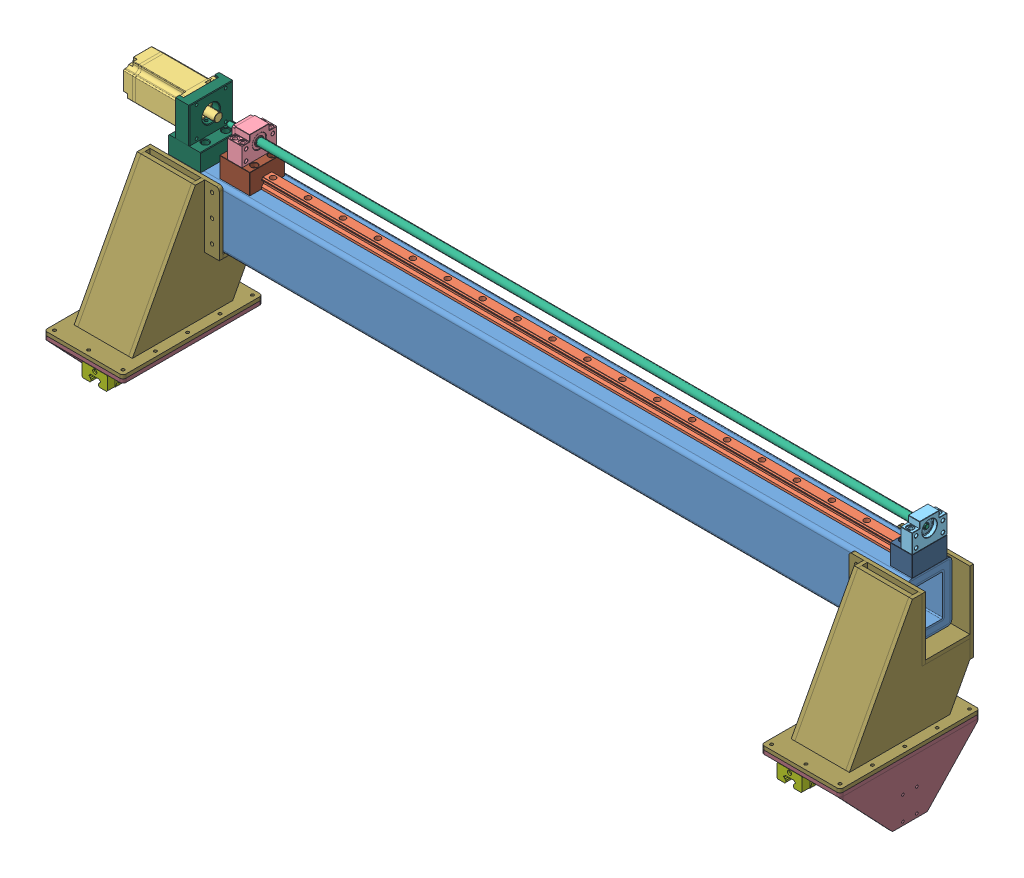
SolidWorks assembly Gantry, configuration Default. Lengths in mm.
Overall size (1404.15 401.35 247).
30 component instances, 15 part files, 148 mates.
Components (placement in the parent):
- steel gantry-1: steel gantry [CFDST] x (0 0 -1) z (1 0 0) size (76.2 101.6 1270)
- HGR20-1: HGR20 [gantry] at (0 -65.3657 0) x (0 0 -1) z (-1 0 0) size (20 17.5 1100)
- HGR20-2: HGR20 [gantry] at (47 65.2343 0) x (0 0 -1) z (1 0 0) size (20 17.5 1100)
- servo JMC_400W_AC-1: servo JMC_400W_AC [Default] at (-704.5 110.7343 0) x (0 -1 0) z (0 0 1) size (60 133.6 60)
- BK12-1: BK12 [Default] at (-529 110.7343 0) x (0 0 1) z (-1 0 0) size (60 43 30.41)
- BF12-1: BF12 [Default] at (625 110.7343 0) x (0 0 1) z (-1 0 0) size (60 43 20)
- ballscrew-1: ballscrew [X Axis] at (31 110.7343 0) x (0 0 1) z (-1 0 0) size (12.64 12.64 1200)
- HGW20CC-1: HGW20CC [Default] at (-596.9 -181.5657 163.9242) x (0 0 -1) z (1 0 0) size (77.26 24.9 63)
- HGW20CC-2: HGW20CC [Default] at (-596.9 -181.5657 1.1842) x (0 0 -1) z (1 0 0) size (77.26 24.9 63)
- HGW20CC-3: HGW20CC [Default] at (596.9 -181.5657 163.9242) x (0 0 1) z (-1 0 0) size (77.26 24.9 63)
- HGW20CC-4: HGW20CC [Default] at (596.9 -181.5657 1.1842) x (0 0 1) z (-1 0 0) size (77.26 24.9 63)
- SFU1610 nut housing-1: SFU1610 nut housing [Default] at (-657.3 -234.3657 62.5542) x (0 -1 0) z (0 0 1) size (52 40 40)
- nut_XY-1: nut_XY [Default] at (-657.3 -234.3657 90.5542) x (0 -1 0) z (0 0 1) size (48 40 44)
- nut_XY-2: nut_XY [Default] at (657.3 -234.3657 90.5542) x (0 1 0) z (0 0 1) size (48 40 44)
- SFU1610 nut housing-2: SFU1610 nut housing [Default] at (657.3 -234.3657 62.5542) x (0 1 0) z (0 0 1) size (52 40 40)
- BF12 lift-1: BF12 lift [Default] at (616 50.7343 0) x (0 0 -1) z (1 0 0) size (60 35 38)
- BK12 front block-1: BK12 front block [Default] at (-529 50.7343 0) x (0 0 -1) z (1 0 0) size (60 35 52)
- Gantry Riser Top-1: Gantry Riser Top [Left<As Machined>] at (-616.075 -152.8657 82.5542) size (142.58 209.95 247)
- Gantry Riser Bottom-1: Gantry Riser Bottom [Left] at (-616.075 -159.2157 82.5542) size (135.15 101.15 240)
- Gantry Riser Bottom-2: Gantry Riser Bottom [Right] at (616.075 -159.2157 82.5542) size (135.15 101.15 240)
- Gantry Riser Top-2: Gantry Riser Top [Right] at (616.075 -152.8657 82.5542) size (142.58 209.95 247)
- socket head cap screw_am-1: socket head cap screw_am [B18.3.1M - 6 x 1.0 x 16 Hex SHCS -- 16NHX] at (-570.4 -153.2157 183.9242) x (0 -1 0) z (0 0 1) size (22 10 10)
- socket head cap screw_am-2: socket head cap screw_am [B18.3.1M - 6 x 1.0 x 16 Hex SHCS -- 16NHX] at (-570.4 -153.2157 143.9242) x (0 -1 0) z (0 0 1) size (22 10 10)
- socket head cap screw_am-3: socket head cap screw_am [B18.3.1M - 6 x 1.0 x 16 Hex SHCS -- 16NHX] at (-623.4 -153.2157 143.9242) x (0 -1 0) z (0 0 1) size (22 10 10)
- socket head cap screw_am-4: socket head cap screw_am [B18.3.1M - 6 x 1.0 x 16 Hex SHCS -- 16NHX] at (-623.4 -153.2157 183.9242) x (0 -1 0) z (0 0 1) size (22 10 10)
- socket head cap screw_am-6: socket head cap screw_am [B18.3.1M - 6 x 1.0 x 16 Hex SHCS -- 16NHX] at (-570.4 -153.2157 -18.8158) x (0 -1 0) z (0 0 1) size (22 10 10)
- socket head cap screw_am-7: socket head cap screw_am [B18.3.1M - 6 x 1.0 x 16 Hex SHCS -- 16NHX] at (-623.4 -153.2157 -18.8158) x (0 -1 0) z (0 0 1) size (22 10 10)
- socket head cap screw_am-8: socket head cap screw_am [B18.3.1M - 6 x 1.0 x 16 Hex SHCS -- 16NHX] at (-570.4 -153.2157 21.1842) x (0 -1 0) z (0 0 1) size (22 10 10)
- socket head cap screw_am-9: socket head cap screw_am [B18.3.1M - 6 x 1.0 x 16 Hex SHCS -- 16NHX] at (-623.4 -153.2157 21.1842) x (0 -1 0) z (0 0 1) size (22 10 10)
- X Servo Mount-1: X Servo Mount [Default] at (-611.5 110.7343 0) x (0 0 1) z (-1 0 0) size (75 90.25 55)
Mates (geometry in assembly coordinates):
- Coincident2: coincident: point of steel gantry-1
- Coincident3: coincident aligned: plane of steel gantry-1 through (0 0 0) normal (0 1 0)
- Coincident5: coincident anti-aligned: plane of steel gantry-1 through (0 0 0) normal (0 0 -1)
- Coincident7: coincident anti-aligned: plane of steel gantry-1 through (635 50.7343 31.75) normal (0 1 0); plane of BK12 back block gantry-1 through (635 50.7343 37.9) normal (0 -1 0)
- Coincident10: coincident anti-aligned: plane of steel gantry-1 through (635 50.7343 31.75) normal (0 1 0); plane of HGR20-2 through (597 50.7343 10) normal (0 -1 0)
- Width1: width anti-aligned: plane of steel gantry-1 through (635 -44.5157 38.1) normal (0 0 1); plane of steel gantry-1 through (635 44.3843 -38.1) normal (0 0 -1); plane of HGR20-2 through (597 54.5843 -10) normal (0 0 -1); plane of HGR20-2 through (597 54.5843 10) normal (0 0 1)
- Coincident11: coincident anti-aligned: plane of HGR20-2 through (-503 62.5879 9.6464) normal (-1 0 0); plane of BK12 front block gantry-1 through (-503 75.1343 0.1) normal (1 0 0)
- Coincident12: coincident anti-aligned: plane of steel gantry-1 through (635 50.7343 31.75) normal (0 1 0); plane of BK12 front block gantry-1 through (-556.5 50.7343 -37.9) normal (0 -1 0)
- Coincident13: coincident anti-aligned: plane of steel gantry-1 through (635 -44.5157 38.1) normal (0 0 1); plane of BK12 front block gantry-1 through (-556.5 25.3343 38.1) normal (0 0 -1)
- Coincident14: coincident anti-aligned: plane of steel gantry-1 through (635 50.7343 31.75) normal (0 1 0); plane of servo mount gantry-1 through (-580 50.7343 38.1) normal (0 -1 0)
- Coincident15: coincident anti-aligned: plane of steel gantry-1 through (635 -44.5157 38.1) normal (0 0 1); plane of servo mount gantry-1 through (-580 50.7343 38.1) normal (0 0 -1)
- Coincident16: coincident aligned: plane of steel gantry-1 through (-635 -44.5157 31.75) normal (-1 0 0); plane of servo mount gantry-1 through (-635 106.1843 -0.525) normal (-1 0 0)
- Parallel1: parallel: plane of servo mount gantry-1 through (-635 136.4343 46.975) normal (0 1 0); plane of servo JMC_400W_AC-1 through (-616.5 140.7343 -30) normal (0 1 0)
- Concentric2: concentric aligned: cylinder of BK12 front block gantry-1 through (-536.25 59.1343 23.1) axis (0 1 0) radius 2.9; cylinder of BK12-1 through (-535.5 85.7343 23) axis (0 1 0) radius 3.3
- Parallel2: parallel aligned: plane of BK12 front block gantry-1 through (-556.5 75.1343 0.1) normal (-1 0 0); plane of BK12-1 through (-541.5 110.7343 0) normal (-1 0 0)
- Coincident20: coincident anti-aligned: plane of BK12 front block gantry-1 through (-556.5 81.1343 48.2) normal (0 1 0); plane of BK12-1 through (-541.5 85.7343 -30) normal (0 -1 0)
- Parallel3: parallel aligned: plane of steel gantry-1 through (635 -44.5157 38.1) normal (0 0 1); plane of BF12-1 through (615 118.2343 30) normal (0 0 1)
- Coincident22: coincident anti-aligned: plane of BK12 back block gantry-1 through (635 81.1343 -48.2) normal (0 1 0); plane of BF12-1 through (615 85.7343 -30) normal (0 -1 0)
- Coincident23: coincident anti-aligned: plane of BF12-1 through (621 110.7343 -8.1511) normal (-1 0 0); plane of ballscrew-1 through (621 117.0543 0) normal (1 0 0)
- Concentric5: concentric aligned: cylinder of BF12-1 through (625 110.7343 0) axis (-1 0 0) radius 5; cylinder of ballscrew-1 through (-569 110.7343 0) axis (-1 0 0) radius 6.32
- Coincident24: coincident aligned: plane of steel gantry-1 through (635 -44.5157 31.75) normal (1 0 0); plane of BK12 back block gantry-1 through (635 75.1343 -0.1) normal (1 0 0)
- Coincident25: coincident anti-aligned: plane of steel gantry-1 through (635 44.3843 -38.1) normal (0 0 -1); plane of BK12 back block gantry-1 through (635 25.3343 -38.1) normal (0 0 1)
- Coincident26: coincident anti-aligned: plane of HGR20-2 through (597 62.5879 9.6464) normal (1 0 0); plane of BK12 back block gantry-1 through (597 75.1343 -0.1) normal (-1 0 0)
- Concentric6: concentric aligned: cylinder of BK12 back block gantry-1 through (623 58.1343 -23.1) axis (0 1 0) radius 2.9; cylinder of BF12-1 through (625 85.7343 -23) axis (0 1 0) radius 3.3
- Coincident27: coincident anti-aligned: plane of steel gantry-1 through (635 -50.8657 -31.75) normal (0 -1 0); plane of HGR20-1 through (-550 -50.8657 10) normal (0 1 0)
- Width2: width anti-aligned: plane of steel gantry-1 through (635 44.3843 -38.1) normal (0 0 -1); plane of steel gantry-1 through (635 -44.5157 38.1) normal (0 0 1); plane of HGR20-1 through (-550 -54.7157 10) normal (0 0 1); plane of HGR20-1 through (-550 -54.7157 -10) normal (0 0 -1)
- Width3: width anti-aligned: plane of steel gantry-1 through (635 -44.5157 31.75) normal (1 0 0); plane of steel gantry-1 through (-635 -44.5157 31.75) normal (-1 0 0); plane of HGR20-1 through (-550 -62.7192 9.6464) normal (-1 0 0); plane of HGR20-1 through (550 -62.7192 9.6464) normal (1 0 0)
- Parallel4: parallel aligned: plane of ballscrew-1 through (31 110.7343 0) normal (0 1 0)
- Coincident30: coincident aligned: plane of steel gantry-1 through (635 50.7343 31.75) normal (0 1 0); plane of gantry risers-1 through (-647.7 50.7343 176.5) normal (0 1 0)
- Coincident31: coincident anti-aligned: plane of gantry risers-1 through (-356.4052 -165.3757 176.5) normal (0 -1 0); plane of HGW20CC-2 through (-591.545 -165.5657 -77.5988) normal (0 1 0)
- Width5: width anti-aligned: plane of gantry risers-1 through (-647.7 -165.3757 176.5) normal (-1 0 0); plane of gantry risers-1 through (-542.3 -165.3757 176.5) normal (1 0 0); plane of HGW20CC-2 through (-565.4 -174.9214 -77.5988) normal (1 0 0); plane of HGW20CC-2 through (-628.4 -174.9214 -77.5988) normal (-1 0 0)
- Coincident33: coincident aligned: plane of gantry risers-1 through (-356.4052 -165.3757 -21.6883) normal (0 0 -1); plane of HGW20CC-2 through (-587.2536 -178.9042 -37.4458) normal (0 0 -1)
- Coincident35: coincident anti-aligned: plane of steel gantry-1 through (-635 -44.5157 31.75) normal (-1 0 0); plane of gantry risers-1 through (-635 -165.3757 176.5) normal (1 0 0)
- Coincident37: coincident anti-aligned: plane of steel gantry-1 through (635 -44.5157 38.1) normal (0 0 1); plane of gantry risers-1 through (-351.1939 -165.3757 38.1) normal (0 0 -1)
- Coincident38: coincident anti-aligned: plane of steel gantry-1 through (635 -44.5157 31.75) normal (1 0 0); plane of gantry risers-2 through (635 -165.2707 176.5) normal (-1 0 0)
- Coincident39: coincident anti-aligned: plane of steel gantry-1 through (635 -44.5157 38.1) normal (0 0 1); plane of gantry risers-2 through (838.8061 -165.2707 38.1) normal (0 0 -1)
- Coincident40: coincident anti-aligned: plane of steel gantry-1 through (635 -50.8657 -31.75) normal (0 -1 0); plane of gantry risers-2 through (371.3 -50.8657 -33.1) normal (0 1 0)
- Coincident41: coincident anti-aligned: plane of gantry risers-2 through (833.5948 -165.2707 176.5) normal (0 -1 0); plane of HGW20CC-4 through (565.4 -165.5657 79.9672) normal (0 1 0)
- Coincident42: coincident anti-aligned: plane of gantry risers-2 through (833.5948 -165.2707 176.5) normal (0 -1 0); plane of HGW20CC-3 through (591.545 -165.5657 242.7072) normal (0 1 0)
- Coincident43: coincident aligned: plane of gantry risers-2 through (833.5948 -165.2707 176.5) normal (0 0 1); plane of HGW20CC-3 through (587.2536 -178.9042 202.5542) normal (0 0 1)
- Coincident44: coincident aligned: plane of gantry risers-2 through (833.5948 -165.2707 -21.6883) normal (0 0 -1); plane of HGW20CC-4 through (587.2536 -178.9042 -37.4458) normal (0 0 -1)
- Coincident45: coincident aligned: plane of HGW20CC-3 through (628.4 -174.9214 242.7072) normal (1 0 0); plane of HGW20CC-4 through (628.4 -174.9214 79.9672) normal (1 0 0)
- Width6: width aligned: plane of HGW20CC-3 through (628.4 -174.9214 242.7072) normal (1 0 0); plane of HGW20CC-3 through (565.4 -174.9214 242.7072) normal (-1 0 0); plane of gantry risers-2 through (647.7 -165.2707 176.5) normal (1 0 0); plane of gantry risers-2 through (542.3 -165.2707 176.5) normal (-1 0 0)
- Coincident46: coincident anti-aligned: plane of steel gantry-1 through (635 -44.5157 38.1) normal (0 0 1); plane of steel risers-1 through (-635 50.8393 38.1) normal (0 0 -1)
- Coincident47: coincident anti-aligned: plane of steel gantry-1 through (635 -50.8657 -31.75) normal (0 -1 0); plane of steel risers-1 through (-635 -50.8657 33.1) normal (0 1 0)
- Coincident48: coincident aligned: plane of steel gantry-1 through (-635 -44.5157 31.75) normal (-1 0 0); plane of steel risers-1 through (-635 138.1706 -0.2312) normal (-1 0 0)
- Coincident49: coincident aligned: plane of steel gantry-1 through (-635 -44.5157 31.75) normal (-1 0 0); plane of steel plate gantry risers-1 through (-635 -165.1526 176.2522) normal (-1 0 0)
- Coincident50: coincident anti-aligned: plane of steel gantry-1 through (635 -44.5157 38.1) normal (0 0 1); plane of steel plate gantry risers-1 through (-548.5 -50.8657 38.1) normal (0 0 -1)
- Coincident51: coincident anti-aligned: plane of steel gantry-1 through (635 -50.8657 -31.75) normal (0 -1 0); plane of steel plate gantry risers-1 through (-548.5 -50.8657 38.1) normal (0 1 0)
- Width7: width aligned: plane of SFU1610 nut housing-1 through (-657.3 -234.3657 102.5542) normal (0 0 1); plane of steel plate gantry risers-1 through (-657.3 -234.3657 62.5542) normal (0 0 -1); plane of SFU1610 nut housing-1 through (-548.5 -158.8157 196) normal (0 0 1); plane of steel plate gantry risers-1 through (-548.5 -158.8157 -44) normal (0 0 -1)
- Concentric7: concentric anti-aligned: cylinder of SFU1610 nut housing-1 through (-657.3 -234.3657 102.5542) axis (0 0 -1) radius 14; cylinder of nut_XY-1 through (-657.3 -234.3657 108.4825) axis (0 0 1) radius 14
- Coincident53: coincident anti-aligned: plane of SFU1610 nut housing-1 through (-657.3 -234.3657 102.5542) normal (0 0 1); plane of nut_XY-1 through (-633.3 -234.3657 102.5542) normal (0 0 -1)
- Coincident54: coincident aligned: plane of SFU1610 nut housing-1 through (-637.3 -220.3657 102.5542) normal (1 0 0); plane of nut_XY-1 through (-637.3 -254.3657 68.5542) normal (1 0 0)
- Coincident65: coincident aligned: plane of steel gantry-1 through (635 -44.5157 31.75) normal (1 0 0); plane of steel plate gantry risers-2 through (635 -165.1526 176.2522) normal (1 0 0)
- Coincident66: coincident anti-aligned: plane of steel gantry-1 through (635 -50.8657 -31.75) normal (0 -1 0); plane of steel plate gantry risers-2 through (548.5 -50.8657 38.1) normal (0 1 0)
- Coincident67: coincident anti-aligned: plane of steel gantry-1 through (635 44.3843 -38.1) normal (0 0 -1); plane of steel plate gantry risers-2 through (548.5 -50.8657 -38.1) normal (0 0 1)
- Coincident68: coincident anti-aligned: plane of HGW20CC-3 through (591.545 -165.5657 242.7072) normal (0 1 0); plane of steel plate gantry risers-2 through (595 -165.1657 176.2522) normal (0 -1 0)
- Coincident69: coincident anti-aligned: plane of HGW20CC-4 through (591.545 -165.5657 79.9672) normal (0 1 0); plane of steel plate gantry risers-2 through (595 -165.1657 176.2522) normal (0 -1 0)
- Coincident70: coincident aligned: plane of HGW20CC-3 through (587.2536 -178.9042 202.5542) normal (0 0 1); plane of steel plate gantry risers-2 through (548.5 -158.8157 196) normal (0 0 1)
- Coincident71: coincident aligned: plane of HGW20CC-4 through (587.2536 -178.9042 -37.4458) normal (0 0 -1); plane of steel plate gantry risers-2 through (548.5 -158.8157 -44) normal (0 0 -1)
- Coincident73: coincident aligned: plane of SFU1610 nut housing-1 through (-657.3 -234.3657 102.5542) normal (0 0 1); plane of SFU1610 nut housing-2 through (657.3 -234.3657 102.5542) normal (0 0 1)
- Concentric8: concentric anti-aligned: cylinder of nut_XY-2 through (657.3 -234.3657 108.4825) axis (0 0 1) radius 14; cylinder of SFU1610 nut housing-2 through (657.3 -234.3657 102.5542) axis (0 0 -1) radius 14
- Coincident75: coincident aligned: plane of nut_XY-2 through (637.3 -214.3657 68.5542) normal (-1 0 0); plane of SFU1610 nut housing-2 through (637.3 -248.3657 102.5542) normal (-1 0 0)
- Coincident76: coincident anti-aligned: plane of nut_XY-2 through (633.3 -234.3657 102.5542) normal (0 0 -1); plane of SFU1610 nut housing-2 through (657.3 -234.3657 102.5542) normal (0 0 1)
- Concentric9: concentric aligned: cylinder of BF12-1 through (625 85.7343 -23) axis (0 1 0) radius 3.3; cylinder of BF12 lift-1 through (625 50.7343 -23) axis (0 1 0) radius 2.9
- Concentric10: concentric aligned: cylinder of BF12-1 through (625 85.7343 23) axis (0 1 0) radius 3.3; cylinder of BF12 lift-1 through (625 50.7343 23) axis (0 1 0) radius 2.9
- Coincident77: coincident anti-aligned: plane of BF12-1 through (615 85.7343 -30) normal (0 -1 0); plane of BF12 lift-1 through (616 85.7343 0) normal (0 1 0)
- Coincident78: coincident aligned: plane of steel gantry-1 through (635 -44.5157 31.75) normal (1 0 0); plane of BF12 lift-1 through (635 85.7343 -30) normal (1 0 0)
- Coincident79: coincident anti-aligned: plane of steel gantry-1 through (635 50.7343 31.75) normal (0 1 0); plane of BF12 lift-1 through (616 50.7343 0) normal (0 -1 0)
- Width8: width anti-aligned: plane of BF12 lift-1 through (597 85.7343 30) normal (0 0 1); plane of BF12 lift-1 through (597 85.7343 -30) normal (0 0 -1); plane of steel gantry-1 through (635 44.3843 -38.1) normal (0 0 -1); plane of steel gantry-1 through (635 -44.5157 38.1) normal (0 0 1)
- Concentric11: concentric anti-aligned: cylinder of BK12-1 through (-522.5 85.7343 23) axis (0 1 0) radius 3.3; cylinder of BK12 front block-1 through (-522.5 85.7343 23) axis (0 -1 0) radius 2.9
- Concentric12: concentric anti-aligned: cylinder of BK12-1 through (-522.5 85.7343 -23) axis (0 1 0) radius 3.3; cylinder of BK12 front block-1 through (-522.5 85.7343 -23) axis (0 -1 0) radius 2.9
- Coincident80: coincident anti-aligned: plane of BK12-1 through (-541.5 85.7343 -30) normal (0 -1 0); plane of BK12 front block-1 through (-529 85.7343 0) normal (0 1 0)
- Coincident81: coincident anti-aligned: plane of steel gantry-1 through (635 50.7343 31.75) normal (0 1 0); plane of BK12 front block-1 through (-529 50.7343 0) normal (0 -1 0)
- Width9: width aligned: plane of BK12 front block-1 through (-503 85.7343 30) normal (0 0 1); plane of BK12 front block-1 through (-503 85.7343 -30) normal (0 0 -1); plane of steel gantry-1 through (635 -44.5157 38.1) normal (0 0 1); plane of steel gantry-1 through (635 44.3843 -38.1) normal (0 0 -1)
- Coincident82: coincident anti-aligned: plane of HGR20-2 through (-503 62.5879 9.6464) normal (-1 0 0); plane of BK12 front block-1 through (-503 85.7343 -30) normal (1 0 0)
- Coincident83: coincident anti-aligned: plane of HGR20-2 through (597 62.5879 9.6464) normal (1 0 0); plane of BF12 lift-1 through (597 85.7343 -30) normal (-1 0 0)
- Concentric14: concentric aligned: cylinder of servo JMC_400W_AC-1 through (-540.501 110.7343 0) axis (-1 0 0) radius 7; cylinder of ballscrew-1 through (-569 110.7343 0) axis (-1 0 0) radius 4
- Coincident84: coincident anti-aligned: plane of steel gantry-1 through (635 50.7343 31.75) normal (0 1 0); plane of servo motor mount-1 through (-610.5 50.7343 0) normal (0 -1 0)
- Concentric15: concentric anti-aligned: cylinder of servo JMC_400W_AC-1 through (-540.501 110.7343 0) axis (-1 0 0) radius 7; cylinder of servo motor mount-1 through (-616.5 110.7343 0) axis (1 0 0) radius 15
- Coincident85: coincident anti-aligned: plane of servo JMC_400W_AC-1 through (-613.5 110.7343 0) normal (1 0 0); plane of servo motor mount-1 through (-613.5 110.7343 0) normal (-1 0 0)
- Coincident86: coincident aligned: plane of steel gantry-1 through (-635 -44.5157 31.75) normal (-1 0 0); plane of servo motor mount-1 through (-635 50.7343 -42.25) normal (-1 0 0)
- Coincident89: coincident aligned: plane of HGW20CC-2 through (-587.2536 -178.9042 -37.4458) normal (0 0 -1); plane of steel plate gantry risers-1 through (-548.5 -158.8157 -44) normal (0 0 -1)
- Coincident90: coincident aligned: plane of HGW20CC-1 through (-587.2536 -178.9042 202.5542) normal (0 0 1); plane of steel plate gantry risers-1 through (-548.5 -158.8157 196) normal (0 0 1)
- Coincident91: coincident anti-aligned: plane of HGW20CC-1 through (-591.545 -165.5657 85.1412) normal (0 1 0); plane of steel plate gantry risers-1 through (-595 -165.1657 176.2522) normal (0 -1 0)
- Coincident92: coincident anti-aligned: plane of HGW20CC-2 through (-591.545 -165.5657 -77.5988) normal (0 1 0); plane of steel plate gantry risers-1 through (-595 -165.1657 176.2522) normal (0 -1 0)
- Coincident93: coincident aligned: plane of HGW20CC-1 through (-565.4 -174.9214 85.1412) normal (1 0 0); plane of HGW20CC-2 through (-565.4 -174.9214 -77.5988) normal (1 0 0)
- Distance3: distance = 41.9 mm anti-aligned: plane of steel plate gantry risers-1 through (-548.5 -158.8157 -44) normal (1 0 0); plane of HGW20CC-1 through (-590.4 -185.7307 125.2942) normal (-1 0 0)
- Distance4: distance = 41.9 mm anti-aligned: plane of steel plate gantry risers-2 through (548.5 -158.8157 -44) normal (-1 0 0); plane of HGW20CC-3 through (590.4 -185.7307 202.5542) normal (1 0 0)
- Coincident94: coincident anti-aligned: plane of steel plate gantry risers-1 through (-677.3 -165.1657 -151.0833) normal (1 0 0); plane of SFU1610 nut housing-1 through (-677.3 -208.3657 102.5542) normal (-1 0 0)
- Coincident95: coincident aligned: plane of steel plate gantry risers-1 through (-677.3 -259.9657 -151.0833) normal (0 -1 0); plane of SFU1610 nut housing-1 through (-677.3 -260.3657 102.5542) normal (0 -1 0)
- Coincident96: coincident anti-aligned: plane of steel plate gantry risers-2 through (677.3 -165.1657 -151.0833) normal (-1 0 0); plane of SFU1610 nut housing-2 through (677.3 -260.3657 102.5542) normal (1 0 0)
- Coincident97: coincident aligned: plane of steel plate gantry risers-2 through (677.3 -259.9657 -151.0833) normal (0 -1 0); plane of SFU1610 nut housing-2 through (677.3 -260.3657 102.5542) normal (0 -1 0)
- Coincident100: coincident aligned: plane of steel plate gantry risers-1 through (-548.5 -158.8157 196) normal (0 0 1); plane of Gantry Riser Bottom-1 through (-616.075 -159.2157 202.5542) normal (0 0 1)
- Coincident101: coincident aligned: plane of steel plate gantry risers-1 through (-595 -165.1657 176.2522) normal (0 -1 0); plane of Gantry Riser Bottom-1 through (-553.5 -165.5657 202.5642) normal (0 -1 0)
- Coincident102: coincident aligned: plane of steel plate gantry risers-1 through (-548.5 -158.8157 -44) normal (1 0 0); plane of Gantry Riser Bottom-1 through (-548.5 -165.5657 202.5542) normal (1 0 0)
- Coincident103: coincident aligned: plane of Gantry Riser Top-1 through (-548.5 -159.2157 202.5542) normal (0 0 1); plane of Gantry Riser Bottom-1 through (-616.075 -159.2157 202.5542) normal (0 0 1)
- Coincident104: coincident aligned: plane of Gantry Riser Top-1 through (-548.5 -159.2157 -37.4458) normal (1 0 0); plane of Gantry Riser Bottom-1 through (-548.5 -165.5657 202.5542) normal (1 0 0)
- Coincident105: coincident anti-aligned: plane of Gantry Riser Top-1 through (-616.075 -159.2157 82.5542) normal (0 -1 0); plane of Gantry Riser Bottom-1 through (-548.5 -159.2157 202.5542) normal (0 1 0)
- Distance5: distance = 48.65 mm aligned: plane of steel gantry-1 through (-635 -44.5157 31.75) normal (-1 0 0); plane of Gantry Riser Top-1 through (-683.65 -159.2157 -37.4458) normal (-1 0 0)
- Coincident107: coincident anti-aligned: plane of steel gantry-1 through (635 -50.8657 -31.75) normal (0 -1 0); plane of Gantry Riser Top-1 through (-566.075 -50.8657 38.1) normal (0 1 0)
- Coincident108: coincident anti-aligned: plane of steel gantry-1 through (635 -44.5157 38.1) normal (0 0 1); plane of Gantry Riser Top-1 through (-566.075 50.7343 38.1) normal (0 0 -1)
- Distance6: distance = 16.9 mm aligned: plane of Gantry Riser Bottom-1 through (-548.5 -165.5657 202.5542) normal (1 0 0); plane of HGW20CC-1 through (-565.4 -174.9214 85.1412) normal (1 0 0)
- Coincident110: coincident aligned: plane of HGW20CC-1 through (-587.2536 -178.9042 202.5542) normal (0 0 1); plane of Gantry Riser Bottom-1 through (-616.075 -159.2157 202.5542) normal (0 0 1)
- Coincident111: coincident aligned: plane of HGW20CC-2 through (-587.2536 -178.9042 -37.4458) normal (0 0 -1); plane of Gantry Riser Bottom-1 through (-616.075 -159.2157 -37.4458) normal (0 0 -1)
- Coincident112: coincident anti-aligned: plane of HGW20CC-2 through (-591.545 -165.5657 -77.5988) normal (0 1 0); plane of Gantry Riser Bottom-1 through (-553.5 -165.5657 202.5642) normal (0 -1 0)
- Coincident113: coincident aligned: plane of SFU1610 nut housing-1 through (-677.3 -260.3657 102.5542) normal (0 -1 0); plane of Gantry Riser Bottom-1 through (-683.65 -260.3657 202.5542) normal (0 -1 0)
- Coincident114: coincident anti-aligned: plane of SFU1610 nut housing-1 through (-677.3 -208.3657 102.5542) normal (-1 0 0); plane of Gantry Riser Bottom-1 through (-677.3 -260.3657 202.5542) normal (1 0 0)
- Width10: width anti-aligned: plane of Gantry Riser Bottom-1 through (-616.075 -159.2157 -37.4458) normal (0 0 -1); plane of Gantry Riser Bottom-1 through (-616.075 -159.2157 202.5542) normal (0 0 1); plane of SFU1610 nut housing-1 through (-657.3 -234.3657 102.5542) normal (0 0 1); plane of SFU1610 nut housing-1 through (-657.3 -234.3657 62.5542) normal (0 0 -1)
- Parallel5: parallel aligned: plane of servo JMC_400W_AC-1 through (-616.5 140.7343 -30) normal (0 1 0); plane of servo motor mount-1 through (-616.5 140.9843 30.25) normal (0 1 0)
- Coincident116: coincident anti-aligned: plane of Gantry Riser Bottom-2 through (683.65 -159.2157 202.5542) normal (0 1 0); plane of Gantry Riser Top-2 through (616.075 -159.2157 82.5542) normal (0 -1 0)
- Coincident117: coincident aligned: plane of Gantry Riser Bottom-2 through (548.5 -159.2157 202.5542) normal (-1 0 0); plane of Gantry Riser Top-2 through (548.5 -159.2157 -37.4458) normal (-1 0 0)
- Coincident118: coincident aligned: plane of Gantry Riser Bottom-2 through (616.075 -159.2157 202.5542) normal (0 0 1); plane of Gantry Riser Top-2 through (548.5 -159.2157 202.5542) normal (0 0 1)
- Coincident119: coincident anti-aligned: plane of steel gantry-1 through (635 -50.8657 -31.75) normal (0 -1 0); plane of Gantry Riser Top-2 through (566.075 -50.8657 38.1) normal (0 1 0)
- Coincident120: coincident anti-aligned: plane of steel gantry-1 through (635 44.3843 -38.1) normal (0 0 -1); plane of Gantry Riser Top-2 through (546.075 45.7343 -38.1) normal (0 0 1)
- Distance7: distance = 48.65 mm aligned: plane of Gantry Riser Top-2 through (683.65 -159.2157 -37.4458) normal (1 0 0); plane of steel gantry-1 through (635 -44.5157 31.75) normal (1 0 0)
- Width11: width aligned: plane of SFU1610 nut housing-2 through (657.3 -234.3657 102.5542) normal (0 0 1); plane of SFU1610 nut housing-2 through (657.3 -234.3657 62.5542) normal (0 0 -1); plane of Gantry Riser Bottom-2 through (616.075 -159.2157 202.5542) normal (0 0 1); plane of Gantry Riser Bottom-2 through (616.075 -159.2157 -37.4458) normal (0 0 -1)
- Coincident122: coincident aligned: plane of SFU1610 nut housing-2 through (677.3 -260.3657 102.5542) normal (0 -1 0); plane of Gantry Riser Bottom-2 through (683.65 -260.3657 202.5542) normal (0 -1 0)
- Coincident123: coincident anti-aligned: plane of SFU1610 nut housing-2 through (677.3 -260.3657 102.5542) normal (1 0 0); plane of Gantry Riser Bottom-2 through (677.3 -260.3657 202.5542) normal (-1 0 0)
- Coincident124: coincident aligned: plane of HGW20CC-3 through (587.2536 -178.9042 202.5542) normal (0 0 1); plane of Gantry Riser Bottom-2 through (616.075 -159.2157 202.5542) normal (0 0 1)
- Coincident125: coincident aligned: plane of HGW20CC-4 through (587.2536 -178.9042 -37.4458) normal (0 0 -1); plane of Gantry Riser Bottom-2 through (616.075 -159.2157 -37.4458) normal (0 0 -1)
- Coincident126: coincident anti-aligned: plane of HGW20CC-4 through (591.545 -165.5657 79.9672) normal (0 1 0); plane of Gantry Riser Bottom-2 through (678.65 -165.5657 202.5642) normal (0 -1 0)
- Coincident127: coincident anti-aligned: plane of HGW20CC-3 through (591.545 -165.5657 242.7072) normal (0 1 0); plane of Gantry Riser Bottom-2 through (678.65 -165.5657 202.5642) normal (0 -1 0)
- Coincident128: coincident anti-aligned: plane of HGW20CC-1 through (-591.545 -165.5657 85.1412) normal (0 1 0); plane of Gantry Riser Bottom-1 through (-553.5 -165.5657 202.5642) normal (0 -1 0)
- Distance8: distance = 16.9 mm aligned: plane of HGW20CC-3 through (565.4 -174.9214 242.7072) normal (-1 0 0); plane of Gantry Riser Bottom-2 through (548.5 -159.2157 202.5542) normal (-1 0 0)
- Concentric16: concentric anti-aligned: cylinder of Gantry Riser Bottom-1 through (-570.4 -159.2157 183.9242) axis (0 -1 0) radius 3.2; cylinder of socket head cap screw_am-1 through (-570.4 -121.4657 183.9242) axis (0 1 0) radius 5
- Coincident129: coincident anti-aligned: plane of Gantry Riser Bottom-1 through (-548.5 -159.2157 202.5542) normal (0 1 0); plane of socket head cap screw_am-1 through (-565.4 -159.2157 183.9242) normal (0 -1 0)
- Concentric17: concentric anti-aligned: cylinder of Gantry Riser Bottom-1 through (-570.4 -159.2157 143.9242) axis (0 -1 0) radius 3.2; cylinder of socket head cap screw_am-2 through (-570.4 -121.4657 143.9242) axis (0 1 0) radius 5
- Coincident130: coincident anti-aligned: plane of Gantry Riser Bottom-1 through (-548.5 -159.2157 202.5542) normal (0 1 0); plane of socket head cap screw_am-2 through (-565.4 -159.2157 143.9242) normal (0 -1 0)
- Concentric18: concentric anti-aligned: cylinder of Gantry Riser Bottom-1 through (-623.4 -159.2157 143.9242) axis (0 -1 0) radius 3.2; cylinder of socket head cap screw_am-3 through (-623.4 -121.4657 143.9242) axis (0 1 0) radius 5
- Coincident131: coincident anti-aligned: plane of Gantry Riser Bottom-1 through (-548.5 -159.2157 202.5542) normal (0 1 0); plane of socket head cap screw_am-3 through (-618.4 -159.2157 143.9242) normal (0 -1 0)
- Concentric19: concentric anti-aligned: cylinder of Gantry Riser Bottom-1 through (-623.4 -159.2157 183.9242) axis (0 -1 0) radius 3.2; cylinder of socket head cap screw_am-4 through (-623.4 -121.4657 183.9242) axis (0 1 0) radius 5
- Coincident132: coincident anti-aligned: plane of Gantry Riser Bottom-1 through (-548.5 -159.2157 202.5542) normal (0 1 0); plane of socket head cap screw_am-4 through (-618.4 -159.2157 183.9242) normal (0 -1 0)
- Concentric20: concentric aligned: cylinder of Gantry Riser Bottom-1 through (-623.4 -159.2157 21.1842) axis (0 -1 0) radius 3.2; cylinder of socket head cap screw_am-5 through (-623.4 -199.2402 21.1842) axis (0 -1 0) radius 5
- Concentric21: concentric anti-aligned: cylinder of Gantry Riser Bottom-1 through (-570.4 -159.2157 -18.8158) axis (0 -1 0) radius 3.2; cylinder of socket head cap screw_am-6 through (-570.4 -121.4657 -18.8158) axis (0 1 0) radius 5
- Coincident133: coincident anti-aligned: plane of Gantry Riser Bottom-1 through (-548.5 -159.2157 202.5542) normal (0 1 0); plane of socket head cap screw_am-6 through (-565.4 -159.2157 -18.8158) normal (0 -1 0)
- Concentric22: concentric anti-aligned: cylinder of Gantry Riser Bottom-1 through (-623.4 -159.2157 -18.8158) axis (0 -1 0) radius 3.2; cylinder of socket head cap screw_am-7 through (-623.4 -121.4657 -18.8158) axis (0 1 0) radius 5
- Coincident134: coincident anti-aligned: plane of Gantry Riser Bottom-1 through (-548.5 -159.2157 202.5542) normal (0 1 0); plane of socket head cap screw_am-7 through (-618.4 -159.2157 -18.8158) normal (0 -1 0)
- Concentric23: concentric anti-aligned: cylinder of Gantry Riser Bottom-1 through (-570.4 -159.2157 21.1842) axis (0 -1 0) radius 3.2; cylinder of socket head cap screw_am-8 through (-570.4 -121.4657 21.1842) axis (0 1 0) radius 5
- Coincident135: coincident anti-aligned: plane of Gantry Riser Bottom-1 through (-548.5 -159.2157 202.5542) normal (0 1 0); plane of socket head cap screw_am-8 through (-565.4 -159.2157 21.1842) normal (0 -1 0)
- Concentric24: concentric anti-aligned: cylinder of Gantry Riser Bottom-1 through (-623.4 -159.2157 21.1842) axis (0 -1 0) radius 3.2; cylinder of socket head cap screw_am-9 through (-623.4 -121.4657 21.1842) axis (0 1 0) radius 5
- Coincident136: coincident anti-aligned: plane of Gantry Riser Bottom-1 through (-548.5 -159.2157 202.5542) normal (0 1 0); plane of socket head cap screw_am-9 through (-618.4 -159.2157 21.1842) normal (0 -1 0)
- Coincident138: coincident anti-aligned: plane of steel gantry-1 through (635 50.7343 31.75) normal (0 1 0); plane of X Servo Mount-1 through (-678.5 50.7343 37.5) normal (0 -1 0)
- Coincident139: coincident aligned: plane of servo motor mount-1 through (-580 50.7343 -42.25) normal (1 0 0); plane of X Servo Mount-1 through (-580 50.7343 -37.5) normal (1 0 0)
- Concentric25: concentric aligned: cylinder of servo JMC_400W_AC-1 through (-613.5 110.7343 0) axis (-1 0 0) radius 25; cylinder of X Servo Mount-1 through (-613.5 110.7343 0) axis (-1 0 0) radius 25.25
- Coincident140: coincident aligned: plane of steel gantry-1 through (-635 -44.5157 31.75) normal (-1 0 0); plane of X Servo Mount-1 through (-635 50.7343 -37.5) normal (-1 0 0)
- Parallel6: parallel aligned: plane of servo JMC_400W_AC-1 through (-616.5 140.7343 -30) normal (0 1 0); plane of X Servo Mount-1 through (-556.5 140.9843 -37.5) normal (0 1 0)
- Coincident142: coincident anti-aligned: plane of servo JMC_400W_AC-1 through (-613.5 110.7343 0) normal (1 0 0); plane of X Servo Mount-1 through (-613.5 110.7343 0) normal (-1 0 0)
